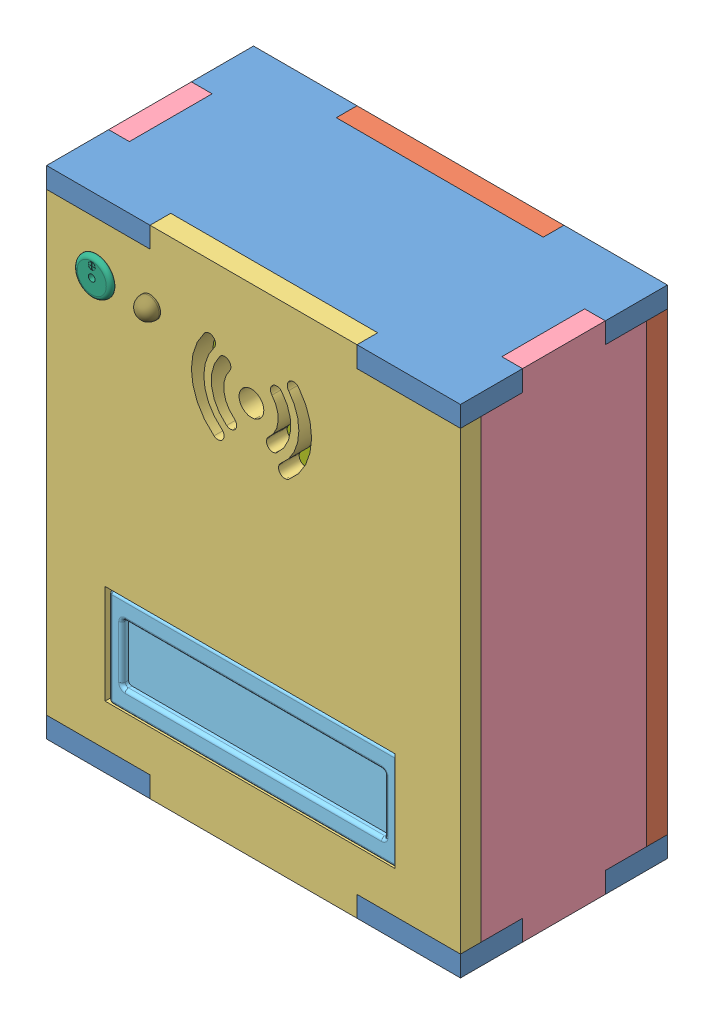
SolidWorks assembly Assemble, configuration Default. Lengths in mm.
Overall size (133.21 120 58.27).
16 component instances, 12 part files, 5 mates.
Components (placement in the parent):
- Bottom_Top-1: Bottom_Top [Default] at (46.6273 34.9892 83.534) size (100 5 50)
- Back-1: Back [Default] at (46.6281 94.9896 57.5492) x (1 -0.000013 0.000309) z (-0.000309 -0.000129 1) size (100 120 5)
- Front-1: Front [Default] at (45.7712 94.9892 102.5492) size (133.21 120 5)
- Bottom_Top-2: Bottom_Top [Default] at (46.6273 149.9892 83.534) size (100 5 50)
- Right_Left-1: Right_Left [Default] at (91.6273 104.9892 82.5492) size (5 120 40)
- Right_Left-2: Right_Left [Default] at (-3.3727 104.9892 82.5492) size (5 120 40)
- LCDScreen-1: LCDScreen [Default] at (46.3534 61.7138 97.7867) x (1 0 0) z (0 -1 0) size (79.38 18.26 34.92)
- Buzzer- Mallory PB-09N23P-03Q-1: Buzzer- Mallory PB-09N23P-03Q [Default] at (8.6273 137.9892 103.1276) x (1 0 0) z (0 -1 0) size (9 13 9)
- RFID-RC522 simple-1: RFID-RC522 simple [По умолчанию] at (46.0349 120.2396 97.5492) x (-0.999962 0.008727 0) z (0 0 1) size (39 59.5 6)
- Switch MIRS-201A-2C3 Red-1: Switch MIRS-201A-2C3 Red [По умолчанию] at (22.0802 121.1044 55.545) x (-1 0.000013 -0.000309) z (0.000309 0.000129 -1) size (15 21.4 27.94)
- battery box up down-2: battery box up down [Default] at (46.6232 74.9876 72.5466) x (1 -0.000013 0.000309) z (-0.000013 -1 -0.000129) size (76 30 5)
- battery box up down-3: battery box up down [Default] at (46.6284 120.1206 72.5494) x (1 0 0) z (0 -0.999962 0.008727) size (76 30 5)
- battery box left right-1: battery box left right [Default] at (3.2793 95.1213 72.6061) x (1 0 0) z (0 -0.999962 0.008727) size (5 30 50)
- battery box left right-2: battery box left right [Default] at (84.2793 95.1202 72.6327) x (1 0 0) z (0 -0.999962 0.008727) size (5 30 50)
- battery box cover-1: battery box cover [Default] at (46.7571 94.9857 82.5467) x (1 -0.000013 0.000309) z (-0.000309 0 1) size (86 50 5)
- led-4: led [Varsayılan] at (79.4773 125.7992 70.2986) size (5.37 5.65 24.29)
Mates (geometry in assembly coordinates):
- Concentric8: concentric aligned: circle of Front-1; circle of RFID-RC522 simple-1
- Coincident30: coincident aligned: line of Back-1 through (38.6277 69.9897 57.5435) axis (1 -0.000013 0.000309); line of battery box up down-2 through (38.6277 69.9897 57.5435) axis (1 -0.000013 0.000309)
- Coincident32: coincident: point of Back-1; point of battery box up down-2
- Coincident34: coincident anti-aligned: line of battery box up down-2 through (54.6185 74.9856 87.5491) axis (-1 0.000013 -0.000309); line of battery box cover-1 through (38.7553 74.9858 87.5442) axis (1 -0.000013 0.000309)
- Concentric9: concentric aligned: circle of Front-1; circle of led-4
